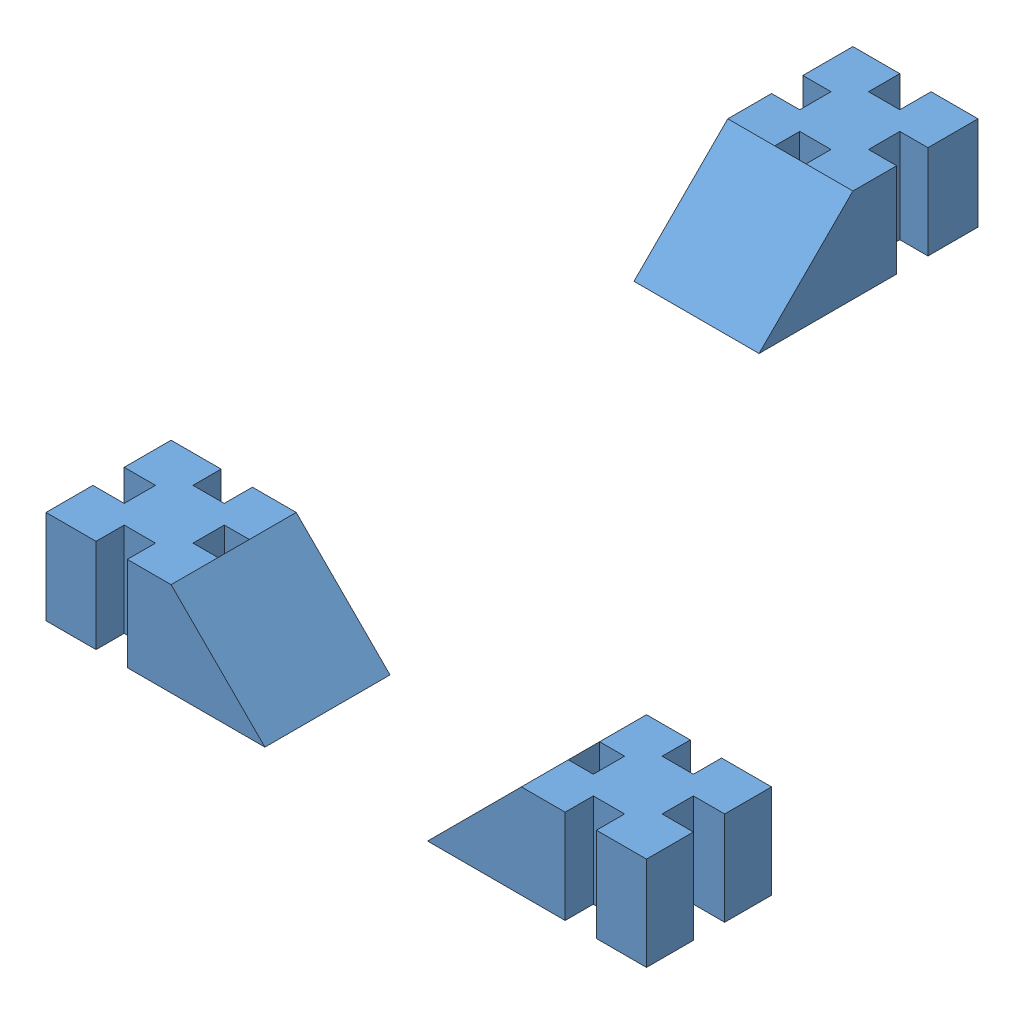
SolidWorks assembly JPAB 2003 6150 L, configuration Default. Lengths in mm.
Overall size (96 15 129).
3 component instances, 1 part files, 0 mates.
Components (placement in the parent):
- square-1: square [Default] at (38 -8.4985 54.5) x (0 0 1) z (1 0 0) size (20 15 35)
- square-5: square [Default] at (-38 -8.4985 54.5) x (0 0 -1) z (-1 0 0) size (20 15 35)
- square-6: square [Default] at (-38 -8.4985 -54.5) x (1 0 0) z (0 0 -1) size (20 15 35)
